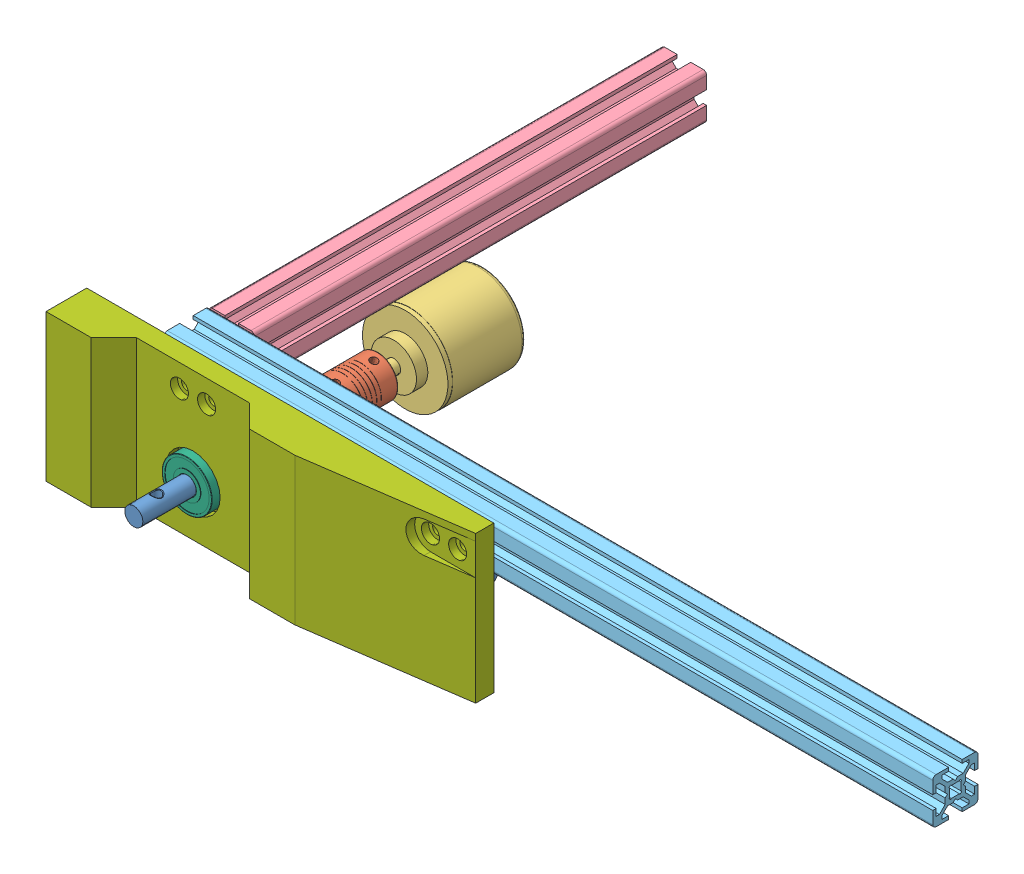
SolidWorks assembly Achse, configuration Default. Lengths in mm.
Overall size (374.1 65 254.17).
8 component instances, 8 part files, 20 mates.
Components (placement in the parent):
- Getriebemotor-1: Getriebemotor [Default] at origin size (115.2 39.7 100)
- Kupplung-1: Kupplung [Default] at (0 0 -42.175) x (-0.239194 -0.970972 0) z (0 0 1) size (18 18.93 25)
- Reifenkupplung_001-1: Reifenkupplung_001 [Default] at (0 0 89.825) x (0.239194 0.970972 0) z (0 0 -1) size (56 56 44) (hidden)
- Encoder-1: Encoder [Default] at (0 0 -88.775) size (38 38 54.6)
- Aluextrusion_200-1: Aluextrusion_200 [Default] at (-10.9 32.85 11.65) x (-1 0 0) z (0 0 -1) size (20 20 200)
- Aluextrusion_350-1: Aluextrusion_350 [Default] at (-20.9 32.85 21.65) x (0 0 -1) z (1 0 0) size (20 20 340)
- Kugellager-1: Kugellager [Default] at (0 0 35.3483) x (0.999852 0.017213 0) z (0 0 1) size (22 22 7)
- Motormontierung-1: Motormontierung [Default] at (-55 -22.15 31.65) size (180 65 18)
Mates (geometry in assembly coordinates):
- Coincident1: coincident aligned: plane of Getriebemotor-1 through (0 0 0) normal (0 0 1)
- Coincident2: coincident aligned: plane of Getriebemotor-1 through (0 0 0) normal (0 1 0)
- Coincident3: coincident aligned: plane of Getriebemotor-1 through (0 0 0) normal (1 0 0)
- Coincident5: coincident anti-aligned: plane of Getriebemotor-1 through (0 0 -34.175) normal (0 0 -1); plane of Kupplung-1 through (0 0 -34.175) normal (0 0 1)
- Concentric1: concentric aligned: cylinder of Getriebemotor-1 through (0 0 -34.175) axis (0 0 1) radius 4; cylinder of Kupplung-1 through (0 0 -34.175) axis (0 0 1) radius 4
- Concentric2: concentric anti-aligned: cylinder of Getriebemotor-1 through (0 0 -34.175) axis (0 0 1) radius 4; cylinder of Reifenkupplung_001-1 through (0 0 65.825) axis (0 0 -1) radius 4
- Coincident6: coincident anti-aligned: plane of Getriebemotor-1 through (0 0 65.825) normal (0 0 1); plane of Reifenkupplung_001-1 through (0 0 65.825) normal (0 0 -1)
- Coincident8: coincident anti-aligned: plane of Getriebemotor-1 through (0 0 -34.175) normal (0 0 -1); plane of Encoder-1 through (0 0 -34.175) normal (0 0 1)
- Concentric3: concentric aligned: cylinder of Kupplung-1 through (0 0 -17.175) axis (0 0 -1) radius 3; cylinder of Encoder-1 through (0 0 -34.175) axis (0 0 -1) radius 3
- Coincident9: coincident aligned: plane of Encoder-1 through (0 0 -88.775) normal (1 0 0)
- Coincident10: coincident anti-aligned: plane of Kupplung-1 through (0 0 -42.175) normal (-0.239194 -0.970972 0); plane of Reifenkupplung_001-1 through (0 0 89.825) normal (0.239194 0.970972 0)
- Concentric4: concentric anti-aligned: cylinder of Getriebemotor-1 through (0 0 -34.175) axis (0 0 1) radius 4; cylinder of Kugellager-1 through (0 0 42.3483) axis (0 0 -1) radius 4
- Coincident23: coincident anti-aligned: plane of Aluextrusion_200-1 through (-10.9 32.85 11.65) normal (0 0 1); plane of Aluextrusion_350-1 through (319.1 35.85 11.65) normal (0 0 -1)
- Coincident24: coincident aligned: plane of Aluextrusion_200-1 through (-13.9 42.85 -188.35) normal (0 1 0); plane of Aluextrusion_350-1 through (319.1 42.85 18.65) normal (0 1 0)
- Coincident25: coincident aligned: plane of Aluextrusion_200-1 through (-20.9 35.85 -188.35) normal (-1 0 0); plane of Aluextrusion_350-1 through (-20.9 32.85 21.65) normal (-1 0 0)
- Distance1: distance = 3 mm anti-aligned: plane of Aluextrusion_350-1 through (319.1 22.85 24.65) normal (0 -1 0); plane of Getriebemotor-1 through (-20.9 19.85 31.65) normal (0 1 0)
- Coincident28: coincident aligned: plane of Getriebemotor-1 through (0 0 31.65) normal (0 0 1); plane of Aluextrusion_350-1 through (319.1 29.85 31.65) normal (0 0 1)
- Coincident29: coincident aligned: plane of Getriebemotor-1 through (-20.9 -19.85 31.65) normal (-1 0 0); plane of Aluextrusion_200-1 through (-20.9 29.85 -188.35) normal (-1 0 0)
- Coincident30: coincident anti-aligned: plane of Getriebemotor-1 through (0 0 31.65) normal (0 0 1); plane of Motormontierung-1 through (124.9048 42.85 31.65) normal (0 0 -1)
- Concentric11: concentric anti-aligned: cylinder of Kugellager-1 through (0 0 42.3483) axis (0 0 -1) radius 11; cylinder of Motormontierung-1 through (0 0 35.35) axis (0 0 1) radius 12
